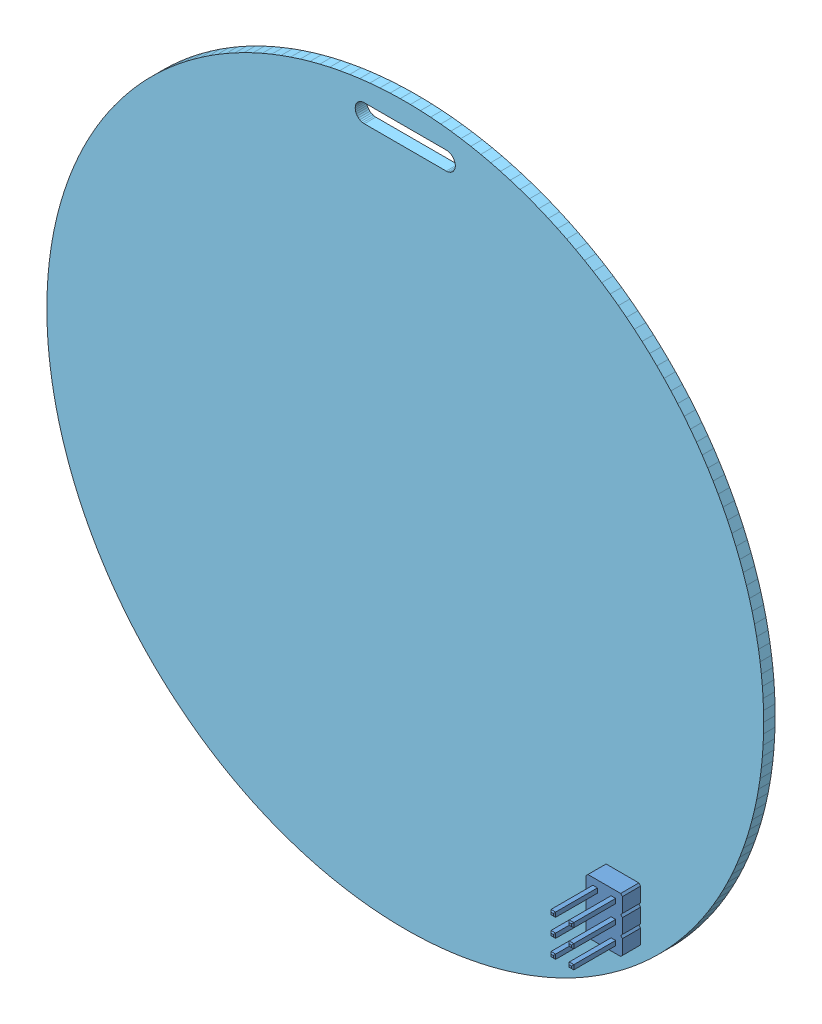
SolidWorks assembly MAGFest2023SolderingClass, configuration Default. Lengths in mm.
Overall size (100 99.99 11.99).
28 component instances, 5 part files, 0 mates.
Components (placement in the parent):
- MAGFest2023SolderingClass.step-1: MAGFest2023SolderingClass.step [Default] at origin size (100 99.99 11.99)
  - PinHeader_2x03_P2.54mm_Vertical.step-1: PinHeader_2x03_P2.54mm_Vertical.step [Default] at (29.083 -29.337 1.65) size (5.08 7.62 11.54)
    - SOLID.STEP-1: SOLID.STEP [Default] at origin size (5.08 7.62 11.54)
  - C_1206_3216Metric.step-1: C_1206_3216Metric.step [Default] at (3.7415 -11.382 -0.05) x (-1 0 0) z (0 0 -1) size (3.2 1.6 1.6)
    - SOLID-0.STEP-1: SOLID-0.STEP [Default] at origin size (3.2 1.6 1.6)
  - R_1206_3216Metric.step-1: R_1206_3216Metric.step [Default] at (9.7215 -17.872 -0.05) x (-1 0 0) z (0 0 -1) size (3.2 1.6 0.55)
    - SOLID-1.STEP-1: SOLID-1.STEP [Default] at origin size (3.2 1.6 0.55)
  - C_1206_3216Metric.step-2: C_1206_3216Metric.step [Default] at (3.7415 -18.082 -0.05) x (-1 0 0) z (0 0 -1) size (3.2 1.6 1.6)
    - SOLID-0.STEP-1: SOLID-0.STEP [Default] at origin size (3.2 1.6 1.6)
  - R_1206_3216Metric.step-2: R_1206_3216Metric.step [Default] at (9.7215 -14.582 -0.05) x (-1 0 0) z (0 0 -1) size (3.2 1.6 0.55)
    - SOLID-1.STEP-1: SOLID-1.STEP [Default] at origin size (3.2 1.6 0.55)
  - SOIC-16_3.9x9.9mm_P1.27mm.step-1: SOIC-16_3.9x9.9mm_P1.27mm.step [Default] at (24.13 -19.05 -0.05) x (-1 0 0) z (0 0 -1) size (6 9.9 1.75)
    - SOLID-2.STEP-1: SOLID-2.STEP [Default] at origin size (6 9.9 1.75)
  - C_1206_3216Metric.step-3: C_1206_3216Metric.step [Default] at (3.7415 -8.032 -0.05) x (-1 0 0) z (0 0 -1) size (3.2 1.6 1.6)
    - SOLID-0.STEP-1: SOLID-0.STEP [Default] at origin size (3.2 1.6 1.6)
  - R_1206_3216Metric.step-3: R_1206_3216Metric.step [Default] at (9.7215 -21.162 -0.05) x (-1 0 0) z (0 0 -1) size (3.2 1.6 0.55)
    - SOLID-1.STEP-1: SOLID-1.STEP [Default] at origin size (3.2 1.6 0.55)
  - R_1206_3216Metric.step-4: R_1206_3216Metric.step [Default] at (9.7215 -8.002 -0.05) x (-1 0 0) z (0 0 -1) size (3.2 1.6 0.55)
    - SOLID-1.STEP-1: SOLID-1.STEP [Default] at origin size (3.2 1.6 0.55)
  - R_1206_3216Metric.step-5: R_1206_3216Metric.step [Default] at (9.7215 -11.292 -0.05) x (-1 0 0) z (0 0 -1) size (3.2 1.6 0.55)
    - SOLID-1.STEP-1: SOLID-1.STEP [Default] at origin size (3.2 1.6 0.55)
  - R_1206_3216Metric.step-6: R_1206_3216Metric.step [Default] at (9.7215 -24.452 -0.05) x (-1 0 0) z (0 0 -1) size (3.2 1.6 0.55)
    - SOLID-1.STEP-1: SOLID-1.STEP [Default] at origin size (3.2 1.6 0.55)
  - SOIC-16_3.9x9.9mm_P1.27mm.step-2: SOIC-16_3.9x9.9mm_P1.27mm.step [Default] at (36.576 -18.034 -0.05) x (0 -1 0) z (0 0 -1) size (6 9.9 1.75)
    - SOLID-2.STEP-1: SOLID-2.STEP [Default] at origin size (6 9.9 1.75)
  - C_1206_3216Metric.step-4: C_1206_3216Metric.step [Default] at (3.7415 -14.732 -0.05) x (-1 0 0) z (0 0 -1) size (3.2 1.6 1.6)
    - SOLID-0.STEP-1: SOLID-0.STEP [Default] at origin size (3.2 1.6 1.6)
  - PCB.STEP-1: PCB.STEP [Default] at origin size (100 99.99 1.6)
